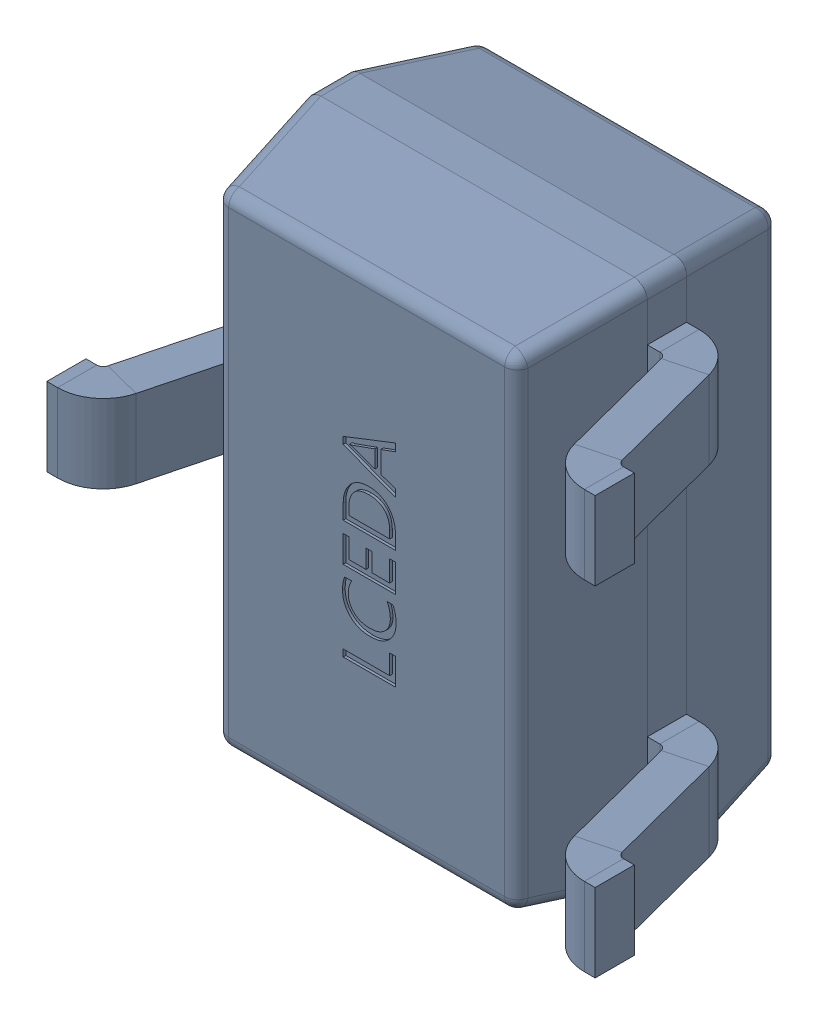
SolidWorks assembly D45, configuration Défaut. Lengths in mm.
Overall size (2.1 2 1.18).
4 component instances, 1 part files, 0 mates.
Components (placement in the parent):
- SOT-323-1: SOT-323 [Défaut] at (5.1841 -12.2543 -0.4818) x (1 0 0) z (0 0 -1) size (2.1 2 1.18)
  - D1.step-1: D1.step [Défaut] at (5.0775 -6.7805 1.6001) size (2.1 2 1.18)
    - SOT-323_L2.0-W1.3-P1.30-LS2.1-BR.step-1: SOT-323_L2.0-W1.3-P1.30-LS2.1-BR.step [Défaut] at origin size (2.1 2 1.18)
      - COMPOUND.step_247-1: COMPOUND.step_247 [Défaut] at origin size (2.1 2 1.18)
